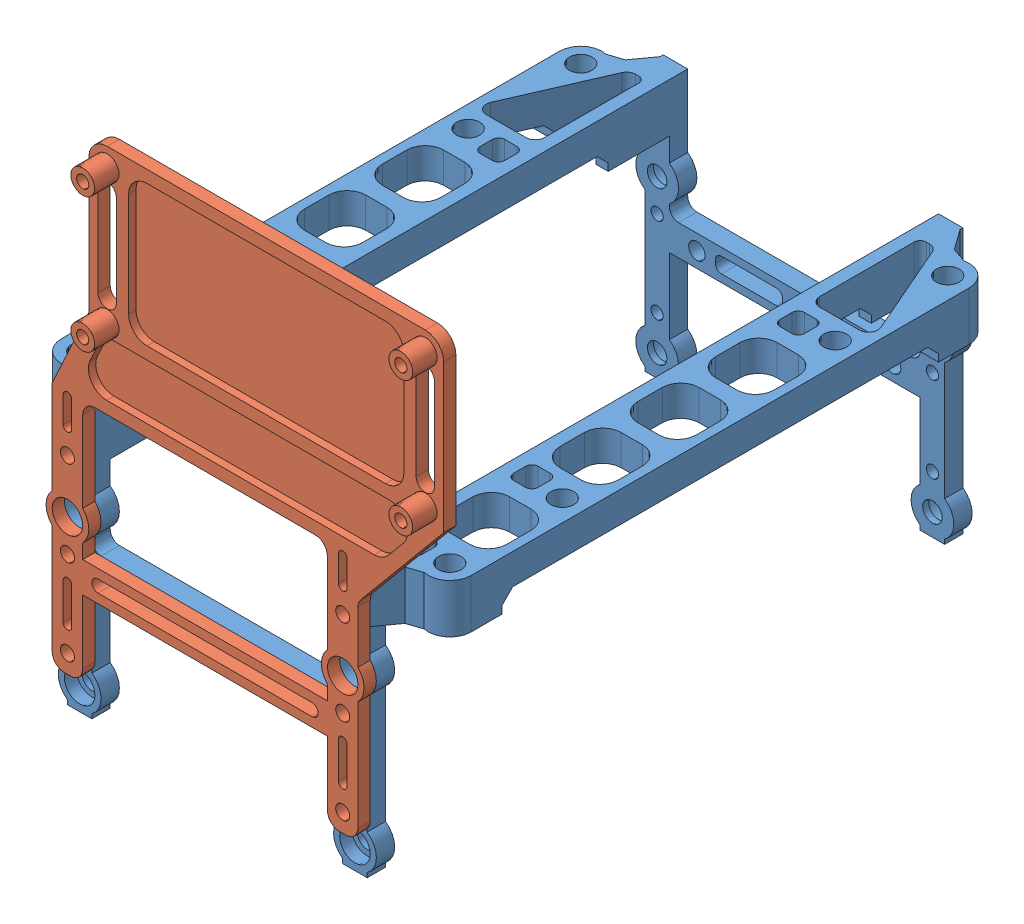
SolidWorks assembly support_livox_and_manifold, configuration Default. Lengths in mm.
Overall size (72.5 84.6 103.4).
2 component instances, 2 part files, 3 mates.
Components (placement in the parent):
- main support mid70 v2-1: main support mid70 v2 [Default] at (-0.7114 -18.0652 54.5594) size (67 43.6 97.4)
- livox_hub_surport-1: livox_hub_surport [Default] at (-21.2114 -8.7652 59.5594) x (-1 0 0) z (0 0 -1) size (65 78 6)
Mates (geometry in assembly coordinates):
- Concentric1: concentric: cylinder of main support mid70 v2-1 through (1.2886 10.5348 55.5594) axis (0 0 1) radius 2.5; cylinder of livox_hub_surport-1 through (1.2886 10.5348 57.5594) axis (0 0 1) radius 2.5
- Parallel1: parallel: plane of main support mid70 v2-1 through (-41.7114 -18.0652 54.5594) normal (1 0 0); plane of livox_hub_surport-1 through (-41.2114 -8.7652 57.5594) normal (1 0 0)
- Coincident2: coincident: plane of main support mid70 v2-1 through (3.2886 -18.0652 57.5594) normal (0 0 1); plane of livox_hub_surport-1 through (-21.2114 -8.7652 57.5594) normal (0 0 -1)
